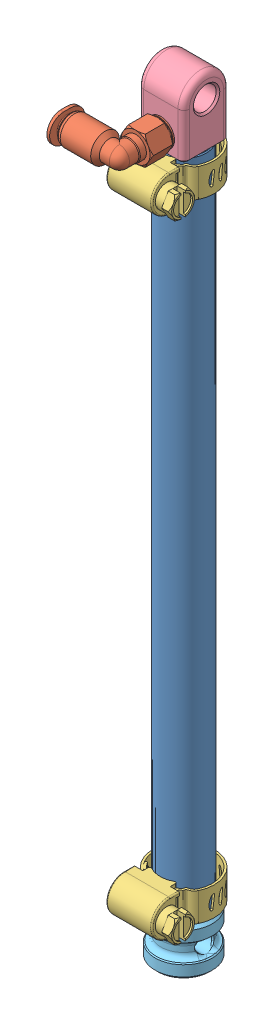
SolidWorks assembly AARL_QR_PN_PA_BR_KN_FL-Flexor, configuration Default. Lengths in mm.
Overall size (26.6 215.9 31.28).
6 component instances, 5 part files, 15 mates.
Components (placement in the parent):
- AARL_QR_PN_PA_BR_KN_FL_001-1: AARL_QR_PN_PA_BR_KN_FL_001 [Resting] at origin size (12.7 184.15 12.7)
- AARL_Puppy_18_02_57_010-QSML-M3-4-1: AARL_Puppy_18_02_57_010-QSML-M3-4 [Default] at (0 96.8375 17.85) x (-1 0 0) z (0 0 -1) size (20.32 8 18.9)
- AARL_Puppy_18_02_57_011-5388K140_Hose-Clamp-1: AARL_Puppy_18_02_57_011-5388K140_Hose-Clamp [5388K14] at (0 -87.122 0) x (1 0 0) z (0 -1 0) size (19.43 23.71 9.91)
- AARL_Puppy_18_02_57_011-5388K140_Hose-Clamp-2: AARL_Puppy_18_02_57_011-5388K140_Hose-Clamp [5388K14] at (0 87.122 0) x (1 0 0) z (0 -1 0) size (19.43 23.71 9.91)
- AARL_QR_PN_EP_001-1: AARL_QR_PN_EP_001 [Default] at (0 104.775 0) x (0 0 1) z (-1 0 0) size (12.7 31.75 12.7)
- AARL_QR_PN_EP_002-1: AARL_QR_PN_EP_002 [Default] at (0 -92.075 0) x (-1 0 0) z (0 0 1) size (15.88 25.4 15.88)
Mates (geometry in assembly coordinates):
- Concentric1: concentric aligned: cylinder of AARL_QR_PN_PA_BR_KN_FL_001-1 through (0 11.6086 0) axis (0 1 0) radius 4.7625; cylinder of AARL_QR_PN_EP_001-1 through (0 114.319 0) axis (0 1 0) radius 4.3656
- Coincident1: coincident anti-aligned: plane of AARL_QR_PN_PA_BR_KN_FL_001-1 through (4.7625 92.075 0) normal (0 1 0); plane of AARL_QR_PN_EP_001-1 through (-6.35 92.075 -6.35) normal (0 -1 0)
- Parallel1: parallel aligned: plane of AARL_QR_PN_EP_001-1 through (-6.35 92.075 6.35) normal (0 0 1)
- Concentric2: concentric aligned: cylinder of AARL_Puppy_18_02_57_010-QSML-M3-4-1 through (0 96.8375 6.35) axis (0 0 1) radius 1.5; cylinder of AARL_QR_PN_EP_001-1 through (0 96.8375 6.35) axis (0 0 1) radius 2.0193
- Parallel2: parallel aligned: plane of AARL_Puppy_18_02_57_010-QSML-M3-4-1 through (2.3094 92.8375 13.4056) normal (0 -1 0); plane of AARL_QR_PN_EP_001-1 through (-6.35 92.075 -6.35) normal (0 -1 0)
- Coincident4: coincident anti-aligned: plane of AARL_Puppy_18_02_57_010-QSML-M3-4-1 through (0 96.8375 6.35) normal (0 0 -1); plane of AARL_QR_PN_EP_001-1 through (-6.35 92.075 6.35) normal (0 0 1)
- Concentric3: concentric anti-aligned: cylinder of AARL_QR_PN_PA_BR_KN_FL_001-1 through (0 11.6086 0) axis (0 1 0) radius 4.7625; cylinder of AARL_QR_PN_EP_002-1 through (0 -99.8127 0) axis (0 -1 0) radius 4.3656
- Coincident5: coincident anti-aligned: plane of AARL_QR_PN_PA_BR_KN_FL_001-1 through (6.35 -92.075 0) normal (0 -1 0); plane of AARL_QR_PN_EP_002-1 through (-4.3656 -92.075 0) normal (0 1 0)
- Parallel3: parallel anti-aligned: cylinder of AARL_QR_PN_EP_001-1 through (-6.35 104.775 0) axis (1 0 0) radius 3.175; cylinder of AARL_QR_PN_EP_002-1 through (7.9375 -98.425 0) axis (-1 0 0) radius 2.3813
- Concentric5: concentric aligned: cylinder of AARL_QR_PN_PA_BR_KN_FL_001-1 through (0 11.6086 0) axis (0 1 0) radius 6.35; cylinder of AARL_Puppy_18_02_57_011-5388K140_Hose-Clamp-2 through (0 83.1532 0) axis (0 1 0) radius 7.9375
- Coincident6: coincident aligned: plane of AARL_Puppy_18_02_57_011-5388K140_Hose-Clamp-2 through (6.35 87.122 10.2337) normal (1 0 0); plane of AARL_QR_PN_EP_001-1 through (6.35 104.775 0) normal (1 0 0)
- Coincident7: coincident anti-aligned: plane of AARL_Puppy_18_02_57_011-5388K140_Hose-Clamp-2 through (0 92.075 0) normal (0 1 0); plane of AARL_QR_PN_EP_001-1 through (-6.35 92.075 -6.35) normal (0 -1 0)
- Concentric6: concentric aligned: cylinder of AARL_QR_PN_PA_BR_KN_FL_001-1 through (0 11.6086 0) axis (0 1 0) radius 6.35; cylinder of AARL_Puppy_18_02_57_011-5388K140_Hose-Clamp-1 through (0 -91.0907 0) axis (0 1 0) radius 7.9375
- Coincident8: coincident aligned: plane of AARL_Puppy_18_02_57_011-5388K140_Hose-Clamp-1 through (6.35 -87.122 10.2337) normal (1 0 0); plane of AARL_Puppy_18_02_57_011-5388K140_Hose-Clamp-2 through (6.35 87.122 10.2337) normal (1 0 0)
- Coincident9: coincident anti-aligned: plane of AARL_Puppy_18_02_57_011-5388K140_Hose-Clamp-1 through (0 -92.075 0) normal (0 -1 0); plane of AARL_QR_PN_EP_002-1 through (-4.3656 -92.075 0) normal (0 1 0)
